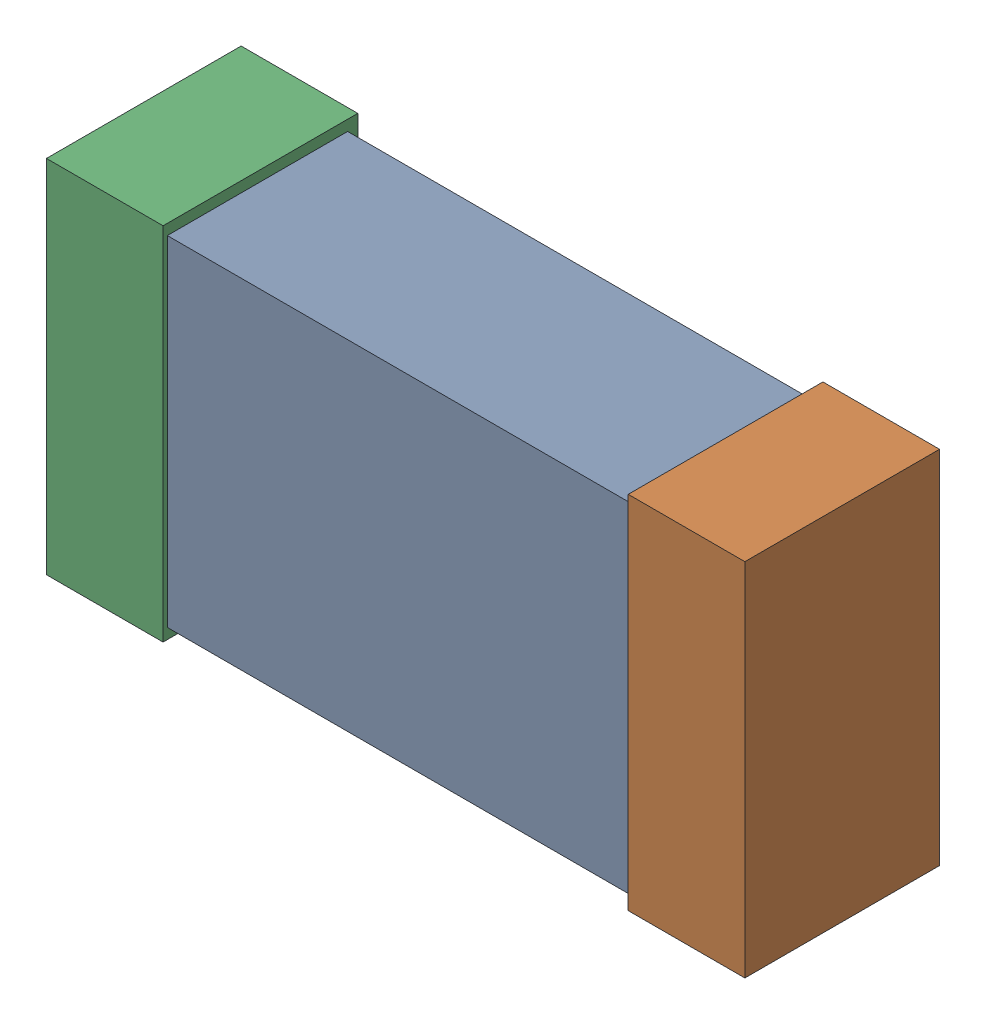
SolidWorks assembly C5, configuration Default. Lengths in mm.
Overall size (1.65 0.85 0.46).
6 component instances, 2 part files, 0 mates.
Components (placement in the parent):
- 432120720_6-1: 432120720_6 [Default] at (28.5457 16.9112 0.025) size (1.5 0.8 0.42)
  - Extruded (12)-1: Extruded (12) [Default] at origin size (1.5 0.8 0.42)
- 432120464_12-1: 432120464_12 [Default] at (29.2315 16.9112 0.001) size (0.28 0.85 0.46)
  - Extruded (11)-1: Extruded (11) [Default] at origin size (0.28 0.85 0.46)
- 432120464_13-1: 432120464_13 [Default] at (27.8599 16.9112 0.001) size (0.28 0.85 0.46)
  - Extruded (11)-1: Extruded (11) [Default] at origin size (0.28 0.85 0.46)
